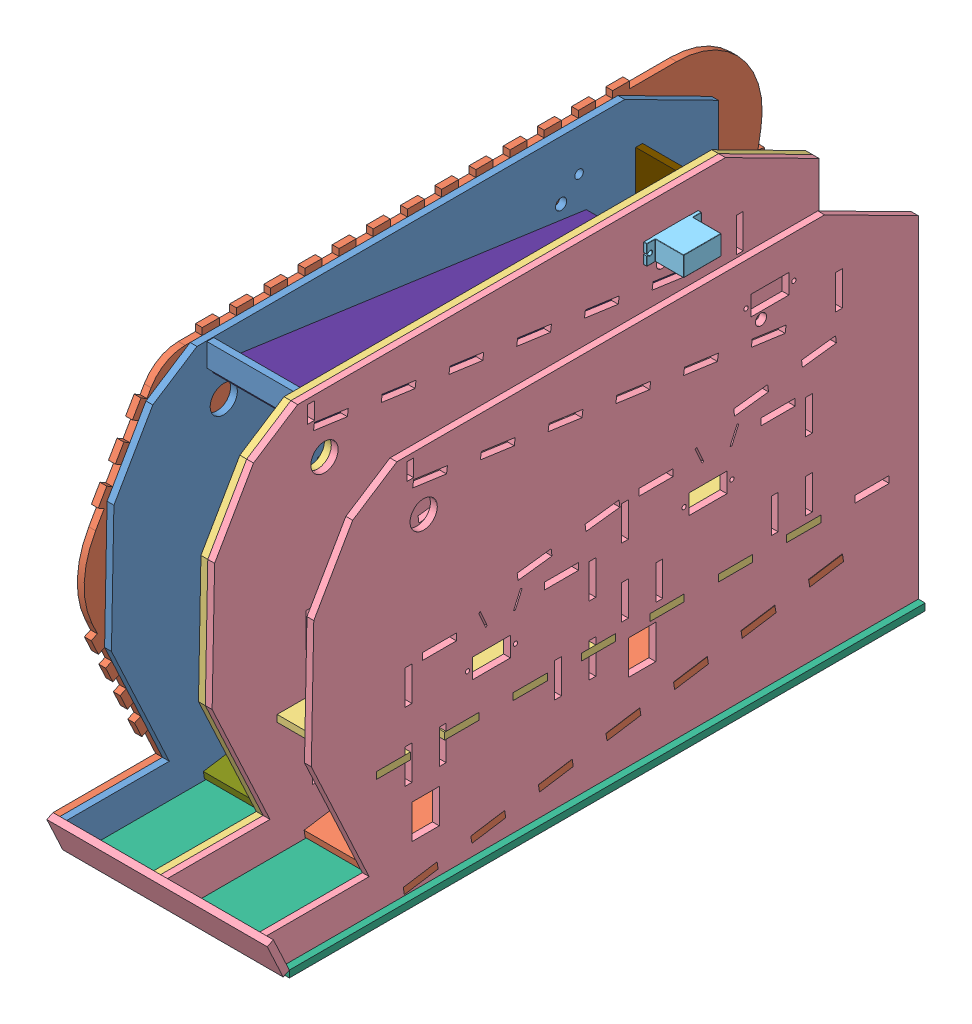
SolidWorks assembly Assembly, configuration По умолчанию. Lengths in mm.
Overall size (128.9 230 415.82).
30 component instances, 23 part files, 81 mates.
Components (placement in the parent):
- wall_1-1: wall_1 [По умолчанию] at origin size (4 226 381.19)
- wall_body-1: wall_body [По умолчанию] at (-8 0 0) size (4 226 412.19)
- wall_1.2-1: wall_1.2 [По умолчанию] at (54.9 0 0) size (4 226 381.19)
- wall_1.3-1: wall_1.3 [По умолчанию] at (58.9 0 0) size (4 226 381.19)
- wall_1.3-2: wall_1.3 [По умолчанию] at (116.9 0 0) size (4 226 381.19)
- servo TOWER PRO 9g SG90-1: servo TOWER PRO 9g SG90 [Défaut] at (81.4 14.1035 -110.3784) x (0 0 1) z (-1 0 0) size (32 11.7 29.7)
- servo TOWER PRO 9g SG90-2: servo TOWER PRO 9g SG90 [Défaut] at (81.4 96.5887 -146.6314) x (0 0 1) z (-1 0 0) size (32 11.7 29.7)
- servo TOWER PRO 9g SG90-3: servo TOWER PRO 9g SG90 [Défaut] at (81.4 -5.75 16.25) x (0 0 1) z (-1 0 0) size (32 11.7 29.7)
- wall_bottom-2: wall_bottom [По умолчанию] at (58.9 -99.2294 -244.4209) size (128.9 4 371.87)
- road 3-1: road 3 [По умолчанию] at (44.9 39.0096 -115.3471) size (4 11.54 40.66)
- road 4-1: road 4 [По умолчанию] at (44.9 40.8879 -93.1289) size (4 9.69 46.37)
- road_12-1: road_12 [По умолчанию] at (7 -2.975 -82.8579) x (0 0 -1) z (0.707107 -0.707107 0) size (24 4 60)
- road-1-1: road-1 [По умолчанию] at (42.7503 62.9811 -233.7067) x (0 0.121869 -0.992546) z (1 0 0) size (60 4 58.9)
- road-1-2: road-1 [По умолчанию] at (42.7503 43.1276 -107.0784) x (0 0.121869 -0.992546) z (1 0 0) size (60 4 58.9)
- road-2-1: road-2 [По умолчанию] at (54.9 38.5277 -152.3313) x (0 0 -1) z (1 0 0) size (26 4 58.9)
- road_10-2: road_10 [По умолчанию] at (54.9 39.8535 -74.8579) size (58.9 89.07 4)
- road_10.1-1: road_10.1 [По умолчанию] at (54.9 39.8535 -94.8579) size (58.9 69.07 4)
- road 3-2: road 3 [По умолчанию] at (10 39.0096 -115.3471) size (4 11.54 40.66)
- road-2-2: road-2 [По умолчанию] at (4 38.5277 -100.9255) x (0 0 1) z (-1 0 0) size (26 4 58.9)
- road 4-2: road 4 [По умолчанию] at (10 40.8879 -93.1289) size (4 9.69 46.37)
- road_10.2-1: road_10.2 [По умолчанию] at (54.9 39.8535 -182.3989) size (58.9 72.07 4)
- road_10.3-1: road_10.3 [По умолчанию] at (54.9 39.8535 -162.3989) size (58.9 52.07 4)
- road-5-1: road-5 [По умолчанию] at (29.45 -54.0482 -200.6283) x (1 0 0) z (0 -0.154893 0.987931) size (58.9 4 260)
- road-5.1-1: road-5.1 [По умолчанию] at (29.45 78.2829 -166.5318) x (1 0 0) z (0 0.139173 0.990268) size (58.9 4 220)
- road-6-1: road-6 [По умолчанию] at (29.45 99.3381 -199.9988) x (0 0 1) z (-1 0 0) size (4 36 58.9)
- road-7-1: road-7 [По умолчанию] at (29.45 126.362 50.7705) x (0 0 1) z (-1 0 0) size (4 13.5 58.9)
- road-5.2-1: road-5.2 [По умолчанию] at (89.9 -54.3565 -200.6766) x (1 0 0) z (0 -0.154893 0.987931) size (62 4 260)
- road-5.3-1: road-5.3 [По умолчанию] at (89.9 -28.1465 -187.3989) size (62 4 260)
- wall_2-1: wall_2 [По умолчанию] at (124.9 -75.2294 136.7705) x (0 -0.422618 0.906308) z (-1 0 0) size (4 22.07 128.9)
- wheel1-1: wheel1 [По умолчанию] at (48.7 19.9309 -126.6897) size (4 61 61)
Mates (geometry in assembly coordinates):
- Совпадение5: coincident aligned: plane of wall_1-1 through (4 -42.8412 91.8734) normal (0 -0.422618 0.906308); plane of wall_body-1 through (-4 -42.8412 91.8734) normal (0 -0.422618 0.906308)
- Расстояние1: distance = 4 mm aligned: plane of wall_body-1 through (-4 0 0) normal (-1 0 0); plane of wall_1-1 through (0 0 0) normal (-1 0 0)
- Совпадение17: coincident anti-aligned: plane of wall_1.2-1 through (58.9 0 0) normal (1 0 0); plane of wall_1.3-1 through (58.9 0 0) normal (-1 0 0)
- Концентричный1: concentric anti-aligned: cylinder of wall_1-1 through (4 0 0) axis (-1 0 0) radius 2.5; cylinder of servo TOWER PRO 9g SG90-3 through (51.7 0 0) axis (1 0 0) radius 2.5
- Концентричный2: concentric anti-aligned: cylinder of wall_1-1 through (4 19.8535 -126.6284) axis (-1 0 0) radius 2.5; cylinder of servo TOWER PRO 9g SG90-1 through (51.7 19.8535 -126.6284) axis (1 0 0) radius 2.5
- Концентричный3: concentric anti-aligned: cylinder of wall_1-1 through (4 102.3387 -162.8814) axis (-1 0 0) radius 2.5; cylinder of servo TOWER PRO 9g SG90-2 through (51.7 102.3387 -162.8814) axis (1 0 0) radius 2.5
- Совпадение23: coincident anti-aligned: plane of wall_1.3-1 through (62.9 0 0) normal (1 0 0); plane of servo TOWER PRO 9g SG90-3 through (62.9 -5.75 16.25) normal (-1 0 0)
- Совпадение24: coincident anti-aligned: plane of wall_1.3-1 through (62.9 0 0) normal (1 0 0); plane of servo TOWER PRO 9g SG90-1 through (62.9 14.1035 -110.3784) normal (-1 0 0)
- Совпадение25: coincident anti-aligned: plane of wall_1.3-1 through (62.9 0 0) normal (1 0 0); plane of servo TOWER PRO 9g SG90-2 through (62.9 96.5887 -146.6314) normal (-1 0 0)
- Совпадение27: coincident anti-aligned: plane of wall_1-1 through (4 -95.2294 0) normal (0 -1 0); plane of wall_bottom-2 through (58.9 -95.2294 -244.4209) normal (0 1 0)
- Совпадение28: coincident anti-aligned: plane of wall_1-1 through (4 0 0) normal (1 0 0); plane of wall_bottom-2 through (4 -95.2294 -244.4209) normal (-1 0 0)
- Совпадение29: coincident anti-aligned: plane of wall_1-1 through (4 0 115.5791) normal (0 0 1); plane of wall_bottom-2 through (58.9 -95.2294 115.5791) normal (0 0 -1)
- Совпадение30: coincident anti-aligned: plane of wall_1.3-2 through (120.9 0 0) normal (1 0 0); plane of wall_bottom-2 through (120.9 -95.2294 -244.4209) normal (-1 0 0)
- Совпадение31: coincident aligned: plane of wall_1.2-1 through (58.9 -95.2294 0) normal (0 -1 0); plane of wall_1.3-1 through (62.9 -95.2294 0) normal (0 -1 0)
- Совпадение32: coincident aligned: plane of wall_1.2-1 through (58.9 0 115.5791) normal (0 0 1); plane of wall_1.3-1 through (62.9 0 115.5791) normal (0 0 1)
- Совпадение33: coincident anti-aligned: plane of wall_1.2-1 through (54.9 0 0) normal (-1 0 0); plane of wall_bottom-2 through (54.9 -95.2294 -244.4209) normal (1 0 0)
- Совпадение34: coincident anti-aligned: plane of wall_1.2-1 through (58.9 -95.2294 0) normal (0 -1 0); plane of wall_bottom-2 through (58.9 -95.2294 -244.4209) normal (0 1 0)
- Совпадение35: coincident anti-aligned: plane of wall_1.2-1 through (58.9 0 115.5791) normal (0 0 1); plane of wall_bottom-2 through (58.9 -95.2294 115.5791) normal (0 0 -1)
- Совпадение36: coincident anti-aligned: plane of wall_1.3-2 through (120.9 -95.2294 0) normal (0 -1 0); plane of wall_bottom-2 through (58.9 -95.2294 -244.4209) normal (0 1 0)
- Совпадение37: coincident anti-aligned: plane of wall_1.3-2 through (120.9 0 95.5791) normal (0 0 -1); plane of wall_bottom-2 through (58.9 -95.2294 95.5791) normal (0 0 1)
- Совпадение38: coincident anti-aligned: plane of wall_body-1 through (-4 -95.2294 0) normal (0 -1 0); plane of wall_bottom-2 through (58.9 -95.2294 -244.4209) normal (0 1 0)
- Совпадение39: coincident anti-aligned: plane of wall_1.2-1 through (54.9 0 0) normal (-1 0 0); plane of road-1-1 through (54.9 59.9438 -176.1479) normal (1 0 0)
- Совпадение40: coincident anti-aligned: plane of wall_1.2-1 through (58.9 17.3225 -141.0807) normal (0 0.121869 -0.992546); plane of road-1-1 through (58.9 55.069 -136.446) normal (0 -0.121869 0.992546)
- Совпадение41: coincident anti-aligned: plane of wall_1.2-1 through (58.9 33.7763 4.1472) normal (0 0.992546 0.121869); plane of road-1-1 through (42.7503 62.9811 -233.7067) normal (0 -0.992546 -0.121869)
- Совпадение42: coincident anti-aligned: plane of wall_1.2-1 through (54.9 0 0) normal (-1 0 0); plane of road-1-2 through (54.9 40.0903 -49.5195) normal (1 0 0)
- Совпадение43: coincident anti-aligned: plane of wall_1.2-1 through (58.9 1.7106 -13.9315) normal (0 0.121869 -0.992546); plane of road-1-2 through (58.9 35.2156 -9.8176) normal (0 -0.121869 0.992546)
- Совпадение44: coincident anti-aligned: plane of wall_1.2-1 through (58.9 33.505 4.1139) normal (0 -0.992546 -0.121869); plane of road-1-2 through (42.7503 47.0978 -106.5909) normal (0 0.992546 0.121869)
- Совпадение48: coincident anti-aligned: plane of wall_1.2-1 through (54.9 0 0) normal (-1 0 0); plane of road-2-1 through (54.9 42.5277 -152.3313) normal (1 0 0)
- Совпадение49: coincident anti-aligned: plane of wall_1.2-1 through (58.9 0 -152.3313) normal (0 0 -1); plane of road-2-1 through (54.9 42.5277 -152.3313) normal (0 0 1)
- Совпадение50: coincident anti-aligned: plane of wall_1.2-1 through (58.9 42.5277 0) normal (0 -1 0); plane of road-2-1 through (54.9 42.5277 -152.3313) normal (0 1 0)
- Совпадение51: coincident anti-aligned: plane of road 3-1 through (48.9 19.9291 -126.6259) normal (1 0 0); plane of road-2-1 through (48.9 42.5277 -152.3313) normal (-1 0 0)
- Совпадение52: coincident anti-aligned: plane of road 3-1 through (48.9 42.5277 -167.3313) normal (0 -1 0); plane of road-2-1 through (54.9 42.5277 -152.3313) normal (0 1 0)
- Совпадение53: coincident anti-aligned: plane of road 3-1 through (48.9 50.0677 -177.3313) normal (0 0 -1); plane of road-2-1 through (54.9 42.5277 -177.3313) normal (0 0 1)
- Совпадение55: coincident anti-aligned: plane of wall_1.2-1 through (54.9 0 0) normal (-1 0 0); plane of road_10-2 through (54.9 39.8535 -70.8579) normal (1 0 0)
- Совпадение56: coincident anti-aligned: plane of wall_1.2-1 through (58.9 0 -70.8579) normal (0 0 -1); plane of road_10-2 through (54.9 39.8535 -70.8579) normal (0 0 1)
- Совпадение57: coincident anti-aligned: plane of wall_1.2-1 through (58.9 39.8535 0) normal (0 -1 0); plane of road_10-2 through (54.9 39.8535 -70.8579) normal (0 1 0)
- Совпадение58: coincident anti-aligned: plane of wall_1.2-1 through (58.9 0 -90.8579) normal (0 0 -1); plane of road_10.1-1 through (54.9 39.8535 -90.8579) normal (0 0 1)
- Совпадение59: coincident anti-aligned: plane of wall_1.2-1 through (54.9 0 0) normal (-1 0 0); plane of road_10.1-1 through (54.9 39.8535 -90.8579) normal (1 0 0)
- Совпадение60: coincident anti-aligned: plane of wall_1.2-1 through (58.9 -0.1465 0) normal (0 -1 0); plane of road_10.1-1 through (54.9 -0.1465 -90.8579) normal (0 1 0)
- Совпадение61: coincident anti-aligned: plane of road_12-1 through (9.8284 -0.1465 -82.8579) normal (0.707107 0.707107 0); plane of road_10-2 through (12.3642 -2.6823 -70.8579) normal (-0.707107 -0.707107 0)
- Совпадение62: coincident anti-aligned: plane of road_12-1 through (9.8284 -0.1465 -74.8579) normal (0 0 1); plane of road_10-2 through (54.9 39.8535 -74.8579) normal (0 0 -1)
- Совпадение63: coincident anti-aligned: plane of road_12-1 through (9.8284 -0.1465 -82.8579) normal (-0.707107 0.707107 0); plane of road_10-2 through (52.3642 42.3893 -70.8579) normal (0.707107 -0.707107 0)
- Совпадение64: coincident anti-aligned: plane of road-2-1 through (10 42.5277 -152.3313) normal (1 0 0); plane of road 3-2 through (10 19.9291 -126.6259) normal (-1 0 0)
- Совпадение65: coincident anti-aligned: plane of road-2-1 through (54.9 42.5277 -177.3313) normal (0 0 1); plane of road 3-2 through (14 50.0677 -177.3313) normal (0 0 -1)
- Совпадение66: coincident anti-aligned: plane of road-2-1 through (54.9 42.5277 -152.3313) normal (0 1 0); plane of road 3-2 through (14 42.5277 -167.3313) normal (0 -1 0)
- Совпадение67: coincident anti-aligned: plane of wall_1.2-1 through (58.9 42.5277 0) normal (0 -1 0); plane of road-2-2 through (4 42.5277 -100.9255) normal (0 1 0)
- Совпадение68: coincident anti-aligned: plane of wall_1.2-1 through (54.9 0 0) normal (-1 0 0); plane of road-2-2 through (54.9 42.5277 -100.9255) normal (1 0 0)
- Совпадение69: coincident anti-aligned: plane of wall_1.2-1 through (58.9 0 -100.9255) normal (0 0 1); plane of road-2-2 through (4 42.5277 -100.9255) normal (0 0 -1)
- Совпадение70: coincident anti-aligned: plane of road-2-2 through (4 42.5277 -100.9255) normal (0 1 0); plane of road 4-2 through (14 42.5277 -95.9255) normal (0 -1 0)
- Совпадение71: coincident anti-aligned: plane of road 4-1 through (48.9 42.5277 -95.9255) normal (0 -1 0); plane of road-2-2 through (4 42.5277 -100.9255) normal (0 1 0)
- Совпадение72: coincident anti-aligned: plane of road-2-2 through (10 42.5277 -100.9255) normal (1 0 0); plane of road 4-2 through (10 19.8733 -126.6422) normal (-1 0 0)
- Совпадение73: coincident anti-aligned: plane of road-2-2 through (4 42.5277 -75.9255) normal (0 0 -1); plane of road 4-2 through (14 38.5277 -75.9255) normal (0 0 1)
- Совпадение74: coincident anti-aligned: plane of road 4-1 through (44.9 19.8733 -126.6422) normal (-1 0 0); plane of road-2-2 through (44.9 42.5277 -100.9255) normal (1 0 0)
- Совпадение75: coincident anti-aligned: plane of road 4-1 through (48.9 38.5277 -95.9255) normal (0 0 1); plane of road-2-2 through (4 42.5277 -95.9255) normal (0 0 -1)
- Совпадение76: coincident: plane of wall_1.2-1 through (54.9 0 0) normal (-1 0 0); line of road_10.2-1 through (54.9 -20.1465 -178.3989) axis (0 -1 0)
- Совпадение77: coincident anti-aligned: plane of wall_1.2-1 through (54.9 0 0) normal (-1 0 0); plane of road_10.3-1 through (54.9 39.8535 -158.3989) normal (1 0 0)
- Совпадение79: coincident anti-aligned: plane of wall_1.2-1 through (58.9 0 -158.3989) normal (0 0 -1); plane of road_10.3-1 through (54.9 39.8535 -158.3989) normal (0 0 1)
- Совпадение80: coincident anti-aligned: plane of wall_1.2-1 through (58.9 -20.1465 0) normal (0 1 0); plane of road_10.3-1 through (54.9 -20.1465 -158.3989) normal (0 -1 0)
- Совпадение81: coincident anti-aligned: plane of wall_1.2-1 through (58.9 0 -178.3989) normal (0 0 -1); plane of road_10.2-1 through (54.9 39.8535 -178.3989) normal (0 0 1)
- Совпадение82: coincident anti-aligned: plane of wall_1.2-1 through (58.9 -20.1465 0) normal (0 1 0); plane of road_10.2-1 through (54.9 -20.1465 -178.3989) normal (0 -1 0)
- Совпадение83: coincident anti-aligned: plane of wall_1.2-1 through (58.9 -79.5006 -12.4645) normal (0 -0.987931 -0.154893); plane of road-5-1 through (29.45 -50.0964 -200.0087) normal (0 0.987931 0.154893)
- Совпадение84: coincident anti-aligned: plane of wall_1.2-1 through (54.9 0 0) normal (-1 0 0); plane of road-5-1 through (54.9 -50.0964 -200.0087) normal (1 0 0)
- Совпадение85: coincident anti-aligned: plane of wall_1.2-1 through (58.9 -10.868 69.3179) normal (0 0.154893 -0.987931); plane of road-5-1 through (29.45 -90.3687 56.8534) normal (0 -0.154893 0.987931)
- Совпадение86: coincident anti-aligned: plane of wall_1.2-1 through (58.9 103.6789 -14.5711) normal (0 -0.990268 0.139173); plane of road-5.1-1 through (29.45 82.2439 -167.0885) normal (0 0.990268 -0.139173)
- Совпадение87: coincident anti-aligned: plane of wall_1.2-1 through (54.9 0 0) normal (-1 0 0); plane of road-5.1-1 through (54.9 82.2439 -167.0885) normal (1 0 0)
- Совпадение88: coincident anti-aligned: plane of wall_1.2-1 through (58.9 -21.4349 -152.5174) normal (0 0.139173 0.990268); plane of road-5.1-1 through (29.45 82.2439 -167.0885) normal (0 -0.139173 -0.990268)
- Совпадение89: coincident anti-aligned: plane of wall_1.2-1 through (54.9 0 0) normal (-1 0 0); plane of road-6-1 through (54.9 99.3381 -195.9988) normal (1 0 0)
- Совпадение90: coincident anti-aligned: plane of wall_1.2-1 through (58.9 0 -199.9988) normal (0 0 1); plane of road-6-1 through (29.45 99.3381 -199.9988) normal (0 0 -1)
- Совпадение91: coincident anti-aligned: plane of wall_1.2-1 through (58.9 94.3381 0) normal (0 -1 0); plane of road-6-1 through (29.45 94.3381 -195.9988) normal (0 1 0)
- Совпадение92: coincident anti-aligned: plane of wall_1.2-1 through (58.9 0 50.7705) normal (0 0 1); plane of road-7-1 through (29.45 126.362 50.7705) normal (0 0 -1)
- Совпадение93: coincident anti-aligned: plane of wall_1.2-1 through (58.9 113.862 0) normal (0 1 0); plane of road-7-1 through (29.45 113.862 54.7705) normal (0 -1 0)
- Совпадение94: coincident anti-aligned: plane of wall_1.2-1 through (54.9 0 0) normal (-1 0 0); plane of road-7-1 through (54.9 126.362 54.7705) normal (1 0 0)
- Совпадение95: coincident anti-aligned: plane of wall_1.3-2 through (120.9 -79.8089 -12.5129) normal (0 -0.987931 -0.154893); plane of road-5.2-1 through (89.9 -50.4048 -200.0571) normal (0 0.987931 0.154893)
- Совпадение96: coincident anti-aligned: plane of wall_1.3-2 through (120.9 -10.868 69.3179) normal (0 0.154893 -0.987931); plane of road-5.2-1 through (89.9 -90.677 56.805) normal (0 -0.154893 0.987931)
- Совпадение97: coincident anti-aligned: plane of wall_1.3-1 through (62.9 0 0) normal (1 0 0); plane of road-5.2-1 through (62.9 -50.4048 -200.0571) normal (-1 0 0)
- Совпадение98: coincident anti-aligned: plane of wall_1.3-2 through (116.9 -24.1465 52.6011) normal (0 -1 0); plane of road-5.3-1 through (89.9 -24.1465 -187.3989) normal (0 1 0)
- Совпадение99: coincident anti-aligned: plane of wall_1.3-1 through (58.9 -24.1465 72.6011) normal (0 0 -1); plane of road-5.3-1 through (89.9 -24.1465 72.6011) normal (0 0 1)
- Совпадение100: coincident anti-aligned: plane of wall_1.3-2 through (116.9 0 0) normal (-1 0 0); plane of road-5.3-1 through (116.9 -24.1465 -187.3989) normal (1 0 0)
- Совпадение101: coincident anti-aligned: plane of wall_1-1 through (4 -65.8226 141.157) normal (0 -0.422618 0.906308); plane of wall_2-1 through (124.9 -75.2294 136.7705) normal (0 0.422618 -0.906308)
- Совпадение102: coincident aligned: plane of wall_bottom-2 through (-4 -95.2294 -244.4209) normal (-1 0 0); plane of wall_2-1 through (-4 -76.9199 140.3957) normal (-1 0 0)
- Совпадение103: coincident: plane of wall_1-1 through (4 -75.2294 0) normal (0 1 0); line of wall_2-1 through (124.9 -75.2294 136.7705) axis (-1 0 0)
